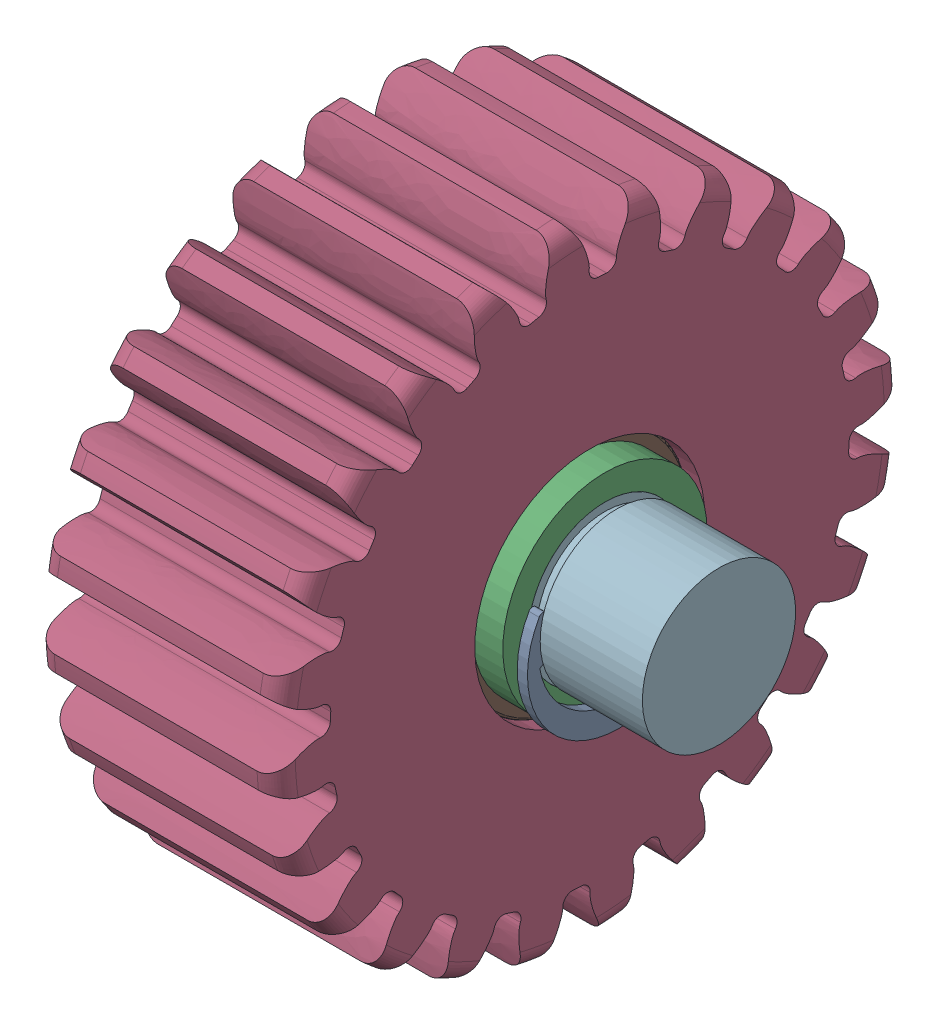
SolidWorks assembly FS2-EN-PT-A-0002-V1, PLANET GEAR, ASSEMBLY, configuration Default. Lengths in mm.
Overall size (30.88 42.24 42.24).
7 component instances, 5 part files, 11 mates.
Components (placement in the parent):
- LOW CLEARANCE EXTERNAL RETAINING RING, 0.375 SIDE MOUNT, 98808A345, MMC-1: LOW CLEARANCE EXTERNAL RETAINING RING, 0.375 SIDE MOUNT, 98808A345, MMC [98808A345] at (-41.8833 78.2683 167.6678) size (0.64 8.6 11.38)
- LOW CLEARANCE EXTERNAL RETAINING RING, 0.375 SIDE MOUNT, 98808A345, MMC-2: LOW CLEARANCE EXTERNAL RETAINING RING, 0.375 SIDE MOUNT, 98808A345, MMC [98808A345] at (-59.3217 78.2683 167.6678) size (0.64 8.6 11.38)
- FS2-EN-PT-P-0004-V1, PLANET SHAFT WASHER, AL SHEET-1: FS2-EN-PT-P-0004-V1, PLANET SHAFT WASHER, AL SHEET [Default] at (-42.2008 79.8034 167.9064) x (0 0.924225 0.381849) z (-1 0 0) size (12.7 12.7 1.91)
- GEAR, 1.5 WIDTH 24 TEETH, KSSA-1: GEAR, 1.5 WIDTH 24 TEETH, KSSA [Default] at (-50.6507 79.8034 167.9064) x (1 0 0) z (0 -0.081784 0.99665) size (15.18 39.17 39.17)
- Needle-Roller Bearing, 0.375 x 0.5, 5905K220, MMC-1: Needle-Roller Bearing, 0.375 x 0.5, 5905K220, MMC [5905K22] at (-50.4558 79.8034 167.9064) x (0 0 -1) z (1 0 0) size (14.29 14.29 12.7)
- FS2-EN-PT-P-0003-V1, PLANET SHAFT, DOWEL PIN-1: FS2-EN-PT-P-0003-V1, PLANET SHAFT, DOWEL PIN [Default] at (-505.5305 -194.6066 167.9064) size (30.87 9.53 9.53)
- FS2-EN-PT-P-0004-V1, PLANET SHAFT WASHER, AL SHEET-2: FS2-EN-PT-P-0004-V1, PLANET SHAFT WASHER, AL SHEET [Default] at (-58.7108 79.8034 167.9064) x (0 0 -1) z (1 0 0) size (12.7 12.7 1.91)
Mates (geometry in assembly coordinates):
- Tangent7: tangent aligned: cylinder of POWERTRAIN-P-0003-V1, PLANET SHAFT, DOWEL PIN-1 through (-65.9892 79.8034 167.9064) axis (-1 0 0) radius 4.2545; cylinder of LOW CLEARANCE EXTERNAL RETAINING RING, 0.375 SIDE MOUNT, 98808A345, MMC-1 through (-41.5658 79.1 167.6678) axis (-1 0 0) radius 4.9973
- Coincident4: coincident anti-aligned: plane of POWERTRAIN-P-0003-V1, PLANET SHAFT, DOWEL PIN-1 through (-42.2008 84.5659 167.9064) normal (1 0 0); plane of LOW CLEARANCE EXTERNAL RETAINING RING, 0.375 SIDE MOUNT, 98808A345, MMC-1 through (-42.2008 79.4539 170.5023) normal (-1 0 0)
- Tangent2: tangent aligned: cylinder of POWERTRAIN-P-0003-V1, PLANET SHAFT, DOWEL PIN-1 through (-65.9892 79.8034 167.9064) axis (-1 0 0) radius 4.2545; cylinder of LOW CLEARANCE EXTERNAL RETAINING RING, 0.375 SIDE MOUNT, 98808A345, MMC-2 through (-59.0042 79.1 167.6678) axis (-1 0 0) radius 4.9973
- Coincident5: coincident anti-aligned: plane of POWERTRAIN-P-0003-V1, PLANET SHAFT, DOWEL PIN-1 through (-59.6392 84.5659 167.9064) normal (1 0 0); plane of LOW CLEARANCE EXTERNAL RETAINING RING, 0.375 SIDE MOUNT, 98808A345, MMC-2 through (-59.6392 79.4539 170.5023) normal (-1 0 0)
- Coincident6: coincident aligned: plane of POWERTRAIN-P-0003-V1, PLANET SHAFT, DOWEL PIN-1 through (-42.2008 84.5659 167.9064) normal (1 0 0); plane of POWERTRAIN-P-0004-V1, PLANET SHAFT WASHER, AL SHEET-1 through (-42.2008 79.8034 167.9064) normal (1 0 0)
- Concentric6: concentric anti-aligned: cylinder of POWERTRAIN-P-0003-V1, PLANET SHAFT, DOWEL PIN-1 through (-65.9892 79.8034 167.9064) axis (-1 0 0) radius 4.7625; cylinder of POWERTRAIN-P-0004-V1, PLANET SHAFT WASHER, AL SHEET-1 through (-44.1058 79.8034 167.9064) axis (1 0 0) radius 6.35
- Coincident8: coincident anti-aligned: plane of POWERTRAIN-P-0004-V1, PLANET SHAFT WASHER, AL SHEET-1 through (-44.1058 79.8034 167.9064) normal (-1 0 0); plane of Needle-Roller Bearing, 0.375 x 0.5, 5905K220, MMC-1 through (-44.1058 86.9472 167.9064) normal (1 0 0)
- Concentric7: concentric anti-aligned: cylinder of POWERTRAIN-P-0003-V1, PLANET SHAFT, DOWEL PIN-1 through (-65.9892 79.8034 167.9064) axis (-1 0 0) radius 4.7625; cylinder of GEAR, 1.5 WIDTH 24 TEETH, KSSA-1 through (-58.2415 79.8034 167.9064) axis (1 0 0) radius 7.1437
- Concentric8: concentric anti-aligned: cylinder of POWERTRAIN-P-0003-V1, PLANET SHAFT, DOWEL PIN-1 through (-65.9892 79.8034 167.9064) axis (-1 0 0) radius 4.7625; cylinder of Needle-Roller Bearing, 0.375 x 0.5, 5905K220, MMC-1 through (-44.1058 79.8034 167.9064) axis (1 0 0) radius 7.1437
- Coincident11: coincident anti-aligned: plane of Needle-Roller Bearing, 0.375 x 0.5, 5905K220, MMC-1 through (-56.8058 84.9628 167.9064) normal (-1 0 0); plane of POWERTRAIN-P-0004-V1, PLANET SHAFT WASHER, AL SHEET-2 through (-56.8058 79.8034 167.9064) normal (1 0 0)
- Concentric15: concentric aligned: cylinder of POWERTRAIN-P-0003-V1, PLANET SHAFT, DOWEL PIN-1 through (-65.9892 79.8034 167.9064) axis (-1 0 0) radius 4.7625; cylinder of POWERTRAIN-P-0004-V1, PLANET SHAFT WASHER, AL SHEET-2 through (-56.8058 79.8034 167.9064) axis (-1 0 0) radius 6.35
